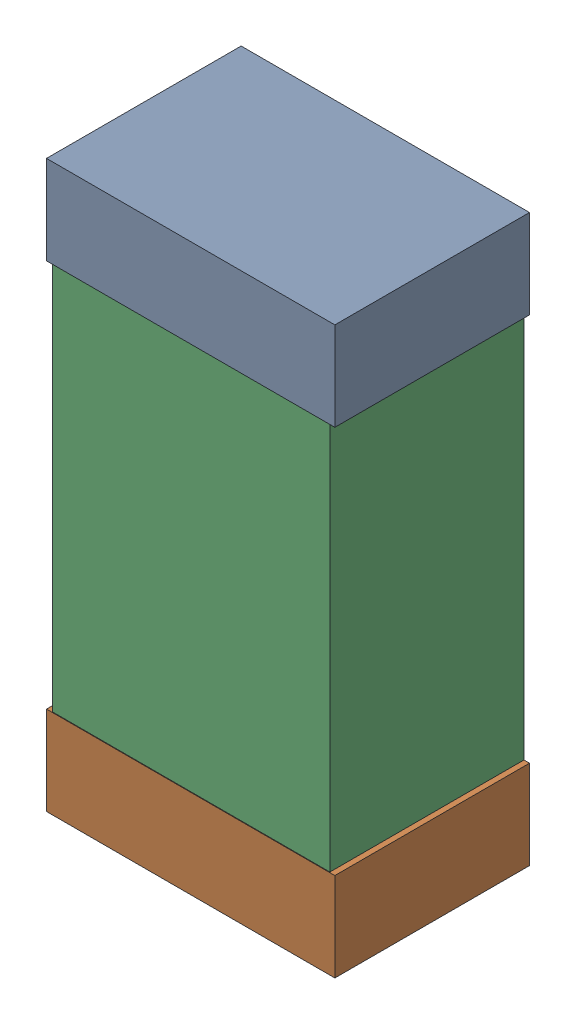
SolidWorks assembly C13, configuration Default. Lengths in mm.
Overall size (0.52 1.02 0.35).
6 component instances, 2 part files, 0 mates.
Components (placement in the parent):
- 870941120-1: 870941120 [Default] at (54.4568 26.4882 0) size (0.52 0.16 0.35)
  - Extruded_3-1: Extruded_3 [Default] at origin size (0.52 0.16 0.35)
- 870941120-2: 870941120 [Default] at (54.4568 25.6282 0) size (0.52 0.16 0.35)
  - Extruded_3-1: Extruded_3 [Default] at origin size (0.52 0.16 0.35)
- 870941280-1: 870941280 [Default] at (54.4568 26.0582 0) size (0.5 1 0.35)
  - Extruded_4-1: Extruded_4 [Default] at origin size (0.5 1 0.35)
